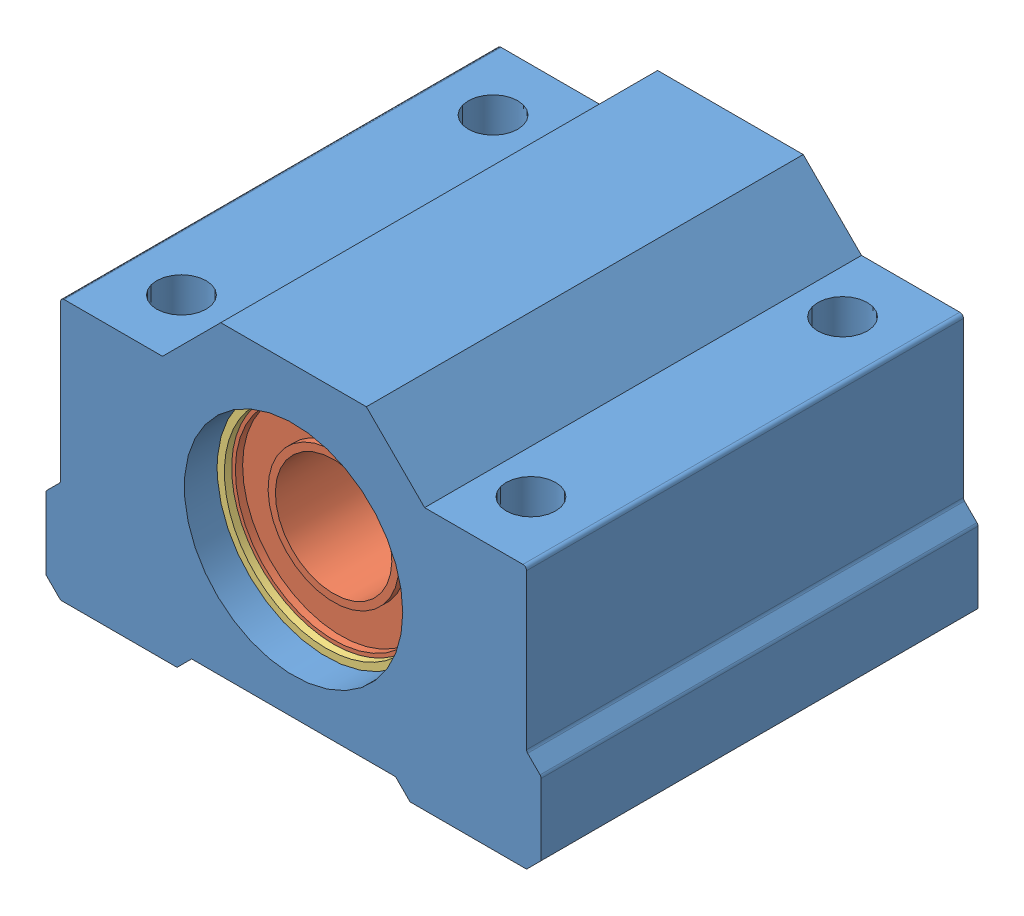
SolidWorks assembly SCS8UU.stp, configuration Default. Lengths in mm.
Overall size (34 22 30).
4 component instances, 3 part files, 0 mates.
Components (placement in the parent):
- SCS8UU_1.stp-1: SCS8UU_1.stp [Default] x (-1 0 0) z (0 0 1) size (34 22 30)
- Lm8uu.stp-1: Lm8uu.stp [Default] at (0 -1.5 0.25) x (0.725053 0.688693 0) z (0 0 1) size (15 15 24)
- E3o.stp-1: E3o.stp [Default] at (0 -1.5 12.5) size (16 15.76 0.5)
- E3o.stp-2: E3o.stp [Default] at (0 -1.5 -12) size (16 15.76 0.5)
